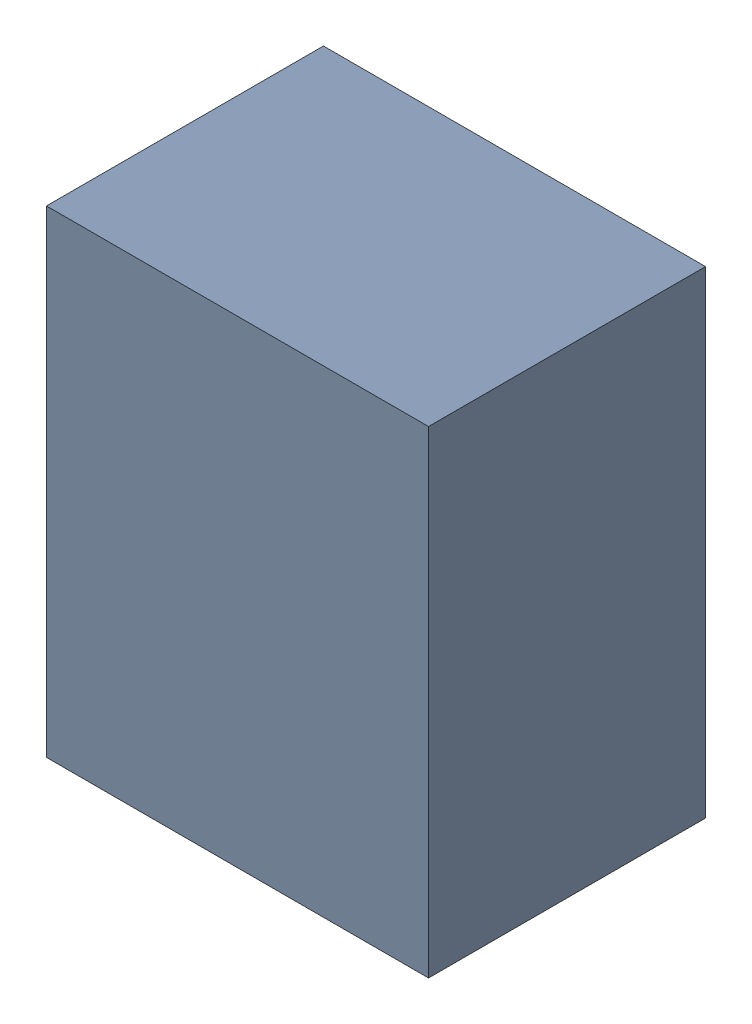
SolidWorks assembly U4, configuration Default. Lengths in mm.
Overall size (0.8 1 0.58).
2 component instances, 1 part files, 0 mates.
Components (placement in the parent):
- 836751984-1: 836751984 [Default] at (102.35 8.1 0.5) size (0.8 1 0.58)
  - Extruded_32-1: Extruded_32 [Default] at origin size (0.8 1 0.58)
